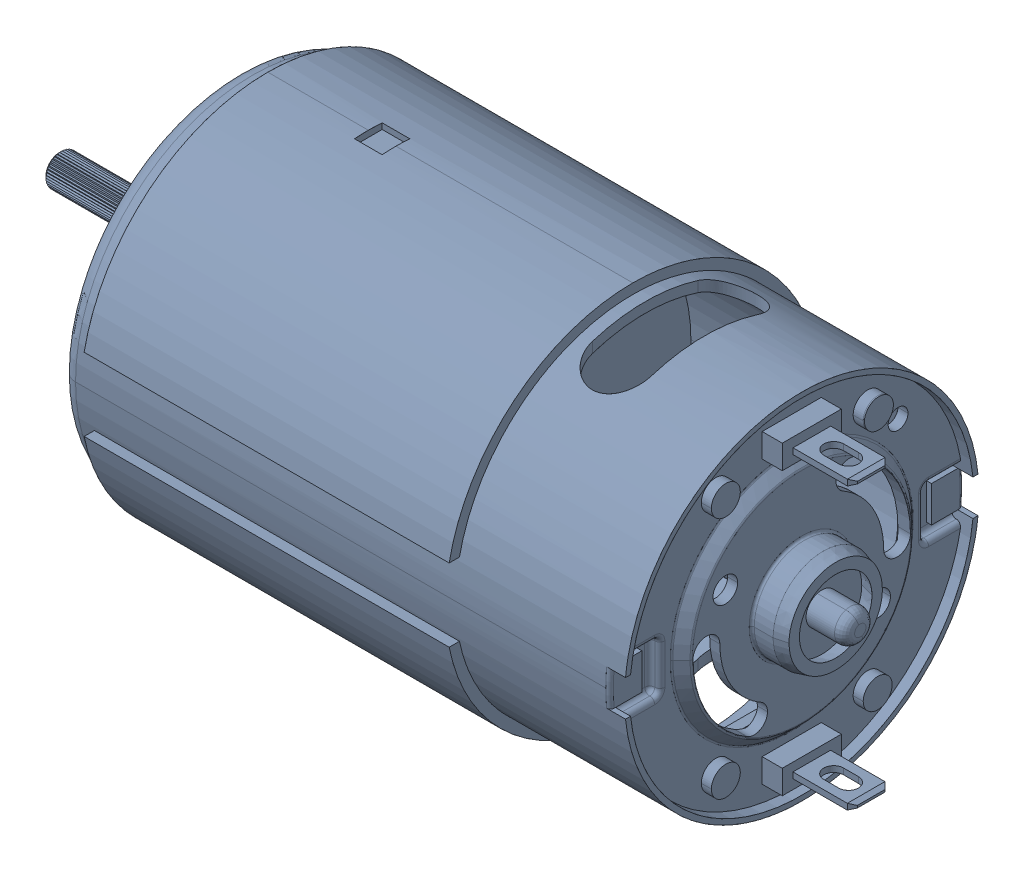
SolidWorks assembly AM-0912, configuration Default. Lengths in mm.
Overall size (82.02 37.83 37.47).
12 component instances, 10 part files, 0 mates.
Components (placement in the parent):
- AM-0912 cap bushing-1: AM-0912 cap bushing [Default] at (31.302 1.123 -1.5904) size (3.04 8.08 8.08)
- AM-0912 red dot-1: AM-0912 red dot [Default] at (32.318 13.4019 -9.2612) size (0.13 2.92 2.92)
- AM-0912 terminal housing-1: AM-0912 terminal housing [Default] at (30.286 -13.101 -1.5904) x (-1 0 0) z (0 0 1) size (4.06 4.83 19.05)
- AM-0912 armature-1: AM-0912 armature [Default] at (1.734 1.123 -1.5904) size (2.54 33.69 33.69)
- AM-0912 end cap-1: AM-0912 end cap [Default] at (24.952 1.123 -1.5904) size (6.48 34.65 34.41)
- AM-0912 shaft-1: AM-0912 shaft [Default] at (-32.682 1.123 -1.5904) x (1 0 0) z (0 0.95755 0.288268) size (80.92 3.2 3.2)
- AM-0912 terminal-1: AM-0912 terminal [Default] at (29.27 -13.055 -1.5854) size (10.06 0.6 3.8)
- AM-0912 shield-1: AM-0912 shield [Default] at (-21.634 1.123 -1.5904) x (1 0 0) z (0 -1 0) size (36.88 37.47 37.83)
- AM-0912 terminal housing-2: AM-0912 terminal housing [Default] at (30.286 15.347 -1.5904) x (-1 0 0) z (0 0 -1) size (4.06 4.83 19.05)
- AM-0912 output bushing-1: AM-0912 output bushing [Default] at (-28.166 1.123 -1.5904) size (4.5 10.97 10.97)
- AM-0912 housing-1: AM-0912 housing [Default] at (32.318 1.123 -1.5904) size (61.5 35.8 35.8)
- AM-0912 terminal-2: AM-0912 terminal [Default] at (29.27 15.301 -1.5954) size (10.06 0.6 3.8)
